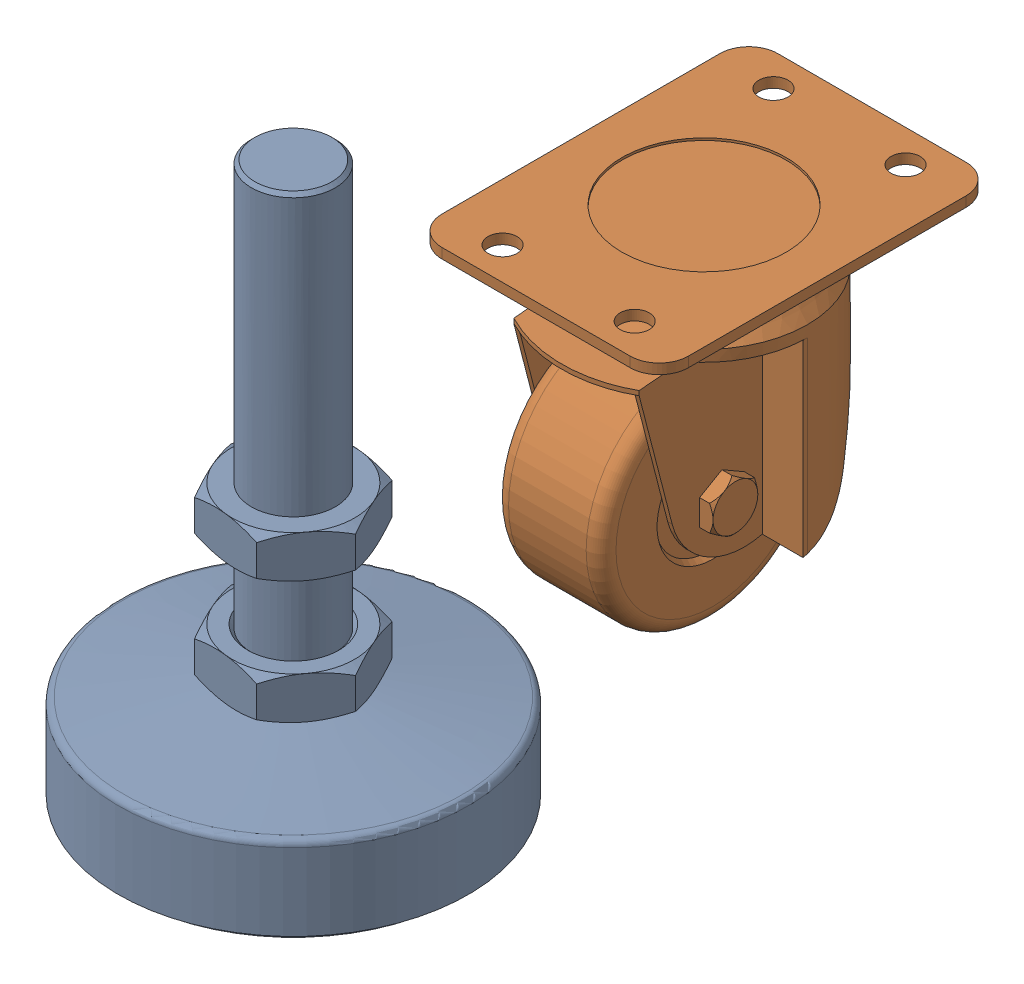
SolidWorks assembly JH-DL160107-01-003D, configuration 默认. Lengths in mm.
Overall size (139.88 159 234.41).
2 component instances, 2 part files, 0 mates.
Components (placement in the parent):
- JH-地脚.SLDPRD-4: JH-地脚.SLDPRD [默认] at (872.6772 -737.3806 1928.0298) x (0.80352 0 0.595278) z (0 -1 0) size (100 100 159)
- JH-万向轮CDZJ100-N_ASM_15__MJUI.SLDPRD-4: JH-万向轮CDZJ100-N_ASM_15__MJUI.SLDPRD [默认] at (873.608 -669.3806 1811.5575) size (70.4 89.6 96)
